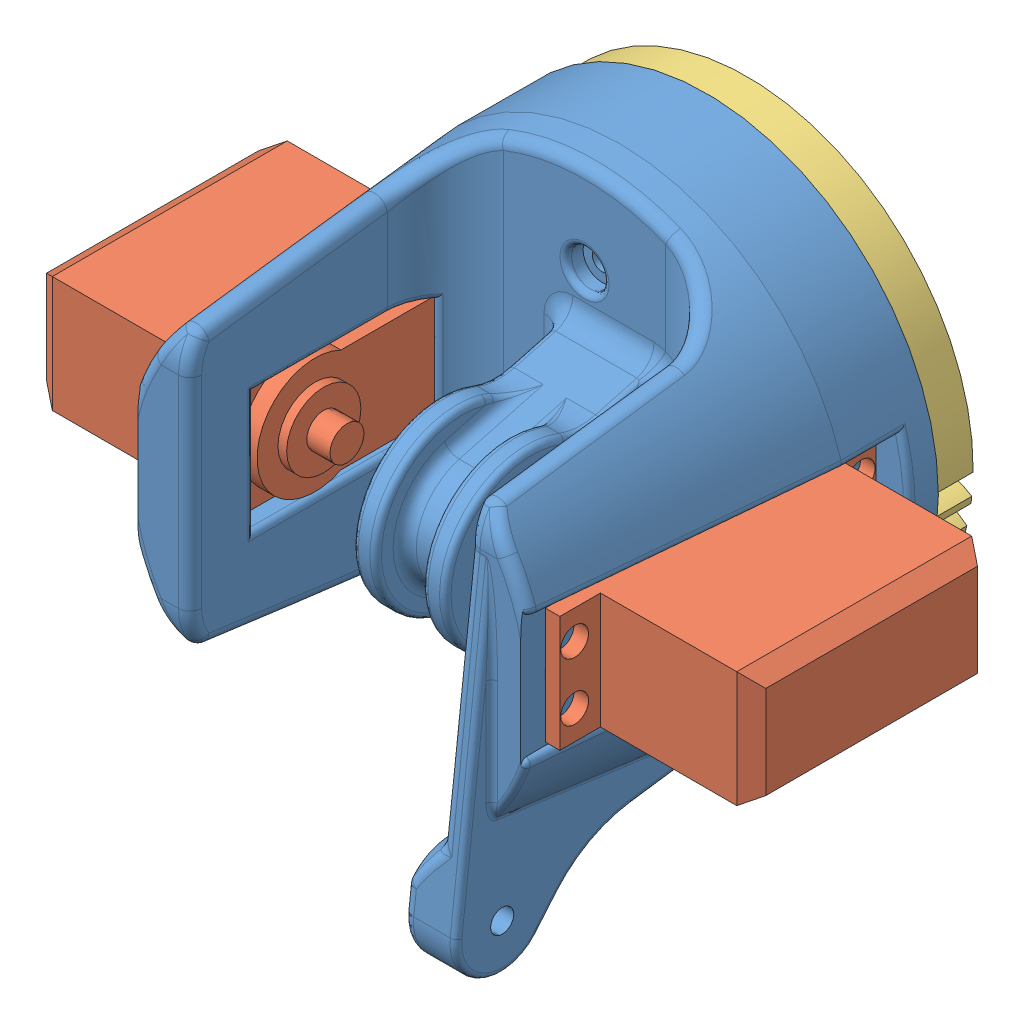
SolidWorks assembly Rotor base.step, configuration Predeterminado. Lengths in mm.
Overall size (124 85.97 83.76).
4 component instances, 3 part files, 0 mates.
Components (placement in the parent):
- 001_base.step-1: 001_base.step [Predeterminado] at origin size (80 85.97 72.76)
- MG946R.step-1: MG946R.step [Predeterminado] at (-55.5 0 33.5) x (0 0 1) z (1 0 0) size (54.5 20 43.3)
- 011_gearmast.step-1: 011_gearmast.step [Predeterminado] at (0 0 -7) x (0 1 0) z (-1 0 0) size (77.97 11.02 78.03)
- MG946R.step-2: MG946R.step [Predeterminado] at (55.5 0 33.5) x (0 0 1) z (-1 0 0) size (54.5 20 43.3)
